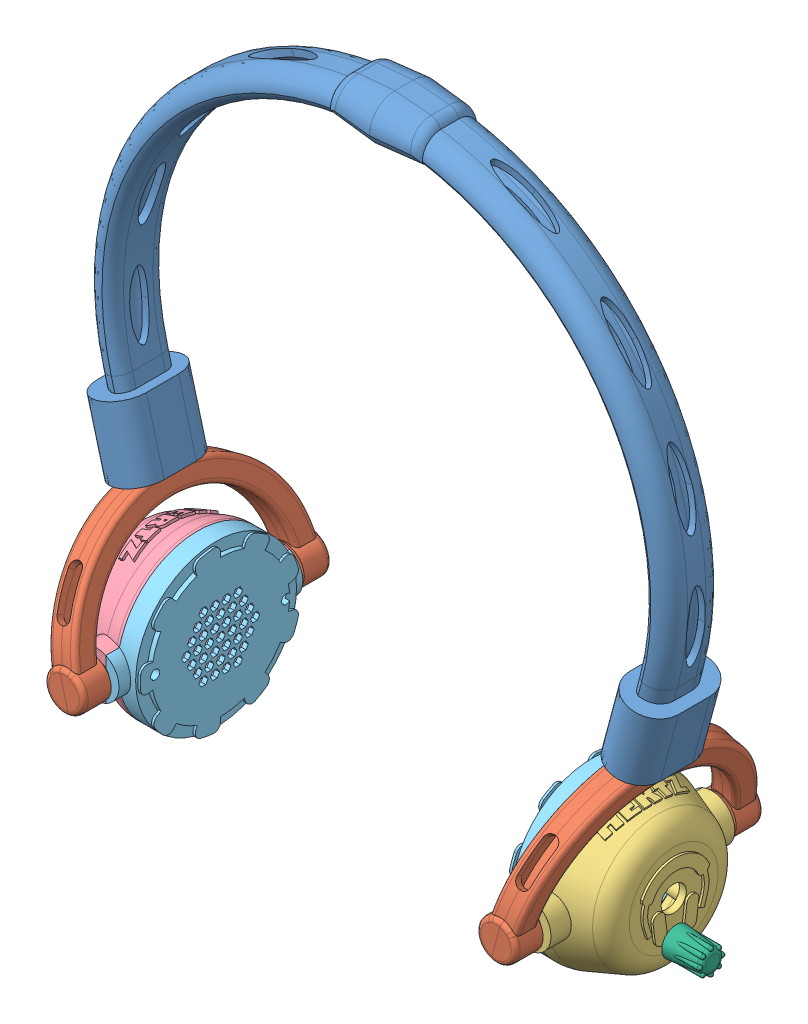
SolidWorks assembly Assem2, configuration Default. Lengths in mm.
Overall size (268.81 283.06 108).
11 component instances, 6 part files, 30 mates.
Components (placement in the parent):
- headband-1: headband [Default] at (155.2293 -27.012 122.3288) size (254.98 199.51 36)
- earcup_connector(sliced)-1: earcup_connector(sliced) [Default] at (142.6655 -16.2312 122.3288) x (0.965926 -0.258819 0) z (0 0 1) size (8.77 82.66 108)
- earcup_connector(sliced)-2: earcup_connector(sliced) [Default] at (-29.8486 -34.1436 122.3288) x (0.965926 0.258819 0) z (0 0 1) size (8.77 82.66 108)
- earcup_connector(sliced)-3: earcup_connector(sliced) [Default] at (37.0011 -16.2312 247.846) x (-0.965926 -0.258819 0) z (0 0 -1) size (8.77 82.66 108)
- earcup_connector(sliced)-4: earcup_connector(sliced) [Default] at (209.5153 -34.1436 247.846) x (-0.965926 0.258819 0) z (0 0 -1) size (8.77 82.66 108)
- earcup_r-1: earcup_r [Default] at (169.6258 4.7646 185.0874) x (0 0 -1) z (1 0 0) size (80 70.22 28.61)
- earcup_l-1: earcup_l [Default] at (10.0408 4.7646 185.0874) x (0 0 1) z (-1 0 0) size (80 70.22 28.61)
- earcup_lid-1: earcup_lid [Default] at (169.6258 4.8002 185.0874) x (0 -0.000416 -1) z (1 0 0) size (80 70 12)
- earcup_lid-2: earcup_lid [Default] at (10.0408 4.8002 185.0874) x (0 -0.000416 1) z (-1 0 0) size (80 70 12)
- pot_cap-1: pot_cap [Default] at (172.5866 -23.999 130.1325) x (1 0 0) z (0 0 1) size (16 12.45 12.45)
- pot_cap-2: pot_cap [Default] at (7.0801 2.3133 130.1455) x (-1 0 0) z (0 0 1) size (16 12.45 12.45)
Mates (geometry in assembly coordinates):
- Coincident1: coincident anti-aligned: plane of earcup_connector(sliced)-2 through (3.5762 -25.1874 122.3288) normal (-0.965926 -0.258819 0); plane of earcup_connector(sliced)-3 through (3.5762 -25.1874 247.846) normal (0.965926 0.258819 0)
- Coincident2: coincident anti-aligned: plane of earcup_connector(sliced)-1 through (176.0904 -25.1874 122.3288) normal (-0.965926 0.258819 0); plane of earcup_connector(sliced)-4 through (176.0904 -25.1874 247.846) normal (0.965926 -0.258819 0)
- Concentric1: concentric anti-aligned: circle of earcup_connector(sliced)-2; circle of earcup_connector(sliced)-3
- Concentric2: concentric anti-aligned: circle of earcup_connector(sliced)-1; circle of earcup_connector(sliced)-4
- Distance1: distance = 5 mm anti-aligned: plane of headband-1 through (-24.6339 80.0942 178.0874) normal (0.258819 -0.965926 0); plane of earcup_connector(sliced)-2 through (-23.3398 75.2646 179.0874) normal (-0.258819 0.965926 0)
- Distance2: distance = 5 mm anti-aligned: plane of earcup_connector(sliced)-1 through (203.0064 75.2646 179.0874) normal (0.258819 0.965926 0); plane of headband-1 through (204.3005 80.0942 178.0874) normal (-0.258819 -0.965926 0)
- Coincident8: coincident aligned: plane of earcup_connector(sliced)-1 through (203.0064 75.2646 179.0874) normal (0.258819 0.965926 0); plane of earcup_connector(sliced)-4 through (203.0064 75.2646 191.0874) normal (0.258819 0.965926 0)
- Coincident9: coincident aligned: plane of earcup_connector(sliced)-2 through (-23.3398 75.2646 179.0874) normal (-0.258819 0.965926 0); plane of earcup_connector(sliced)-3 through (-23.3398 75.2646 191.0874) normal (-0.258819 0.965926 0)
- Concentric9: concentric aligned: circle of earcup_l-1; circle of earcup_lid-2
- Concentric10: concentric aligned: circle of earcup_l-1; circle of earcup_lid-2
- Coincident11: coincident anti-aligned: plane of earcup_l-1; plane of earcup_lid-2
- Concentric11: concentric aligned: circle of earcup_r-1; circle of earcup_lid-1
- Concentric12: concentric aligned: circle of earcup_r-1; circle of earcup_lid-1
- Coincident12: coincident anti-aligned: plane of earcup_r-1; plane of earcup_lid-1
- Concentric13: concentric anti-aligned: circle of earcup_connector(sliced)-1; circle of earcup_r-1
- Concentric14: concentric aligned: circle of earcup_connector(sliced)-2; circle of earcup_l-1
- Width1: width anti-aligned: plane of earcup_connector(sliced)-4 through (183.8373 3.7244 143.0874) normal (0 0 1); plane of earcup_connector(sliced)-4 through (183.8373 3.7244 227.0874) normal (0 0 -1); plane of earcup_r-1 through (183.8373 3.7244 145.0874) normal (0 0 -1); plane of earcup_r-1 through (183.8373 3.7244 225.0874) normal (0 0 1)
- Width2: width anti-aligned: plane of earcup_connector(sliced)-3 through (-4.1706 3.7244 143.0874) normal (0 0 1); plane of earcup_connector(sliced)-3 through (-4.1706 3.7244 227.0874) normal (0 0 -1); plane of earcup_l-1 through (-4.1706 3.7244 145.0874) normal (0 0 -1); plane of earcup_l-1 through (-4.1706 3.7244 225.0874) normal (0 0 1)
- Width3: width anti-aligned: plane of headband-1 through (-17.8724 81.9059 178.0874) normal (-0.965926 -0.258819 0); plane of headband-1 through (-31.3954 78.2825 178.0874) normal (0.965926 0.258819 0); plane of earcup_connector(sliced)-2 through (1.6415 5.2153 134.0881) normal (0.965926 0.258819 0); plane of earcup_connector(sliced)-3 through (-9.9496 2.1095 236.0867) normal (-0.965926 -0.258819 0)
- Width4: width anti-aligned: plane of headband-1 through (197.539 81.9059 178.0874) normal (0.965926 -0.258819 0); plane of headband-1 through (211.062 78.2825 178.0874) normal (-0.965926 0.258819 0); plane of earcup_connector(sliced)-4 through (178.0251 5.2153 236.0867) normal (-0.965926 0.258819 0); plane of earcup_connector(sliced)-1 through (189.6162 2.1095 134.0881) normal (0.965926 -0.258819 0)
- Slot1: slot anti-aligned: plane of earcup_connector(sliced)-1 through (189.6162 2.1095 134.0881) normal (0.965926 -0.258819 0); plane of headband-1 through (211.062 78.2825 178.0874) normal (-0.965926 0.258819 0); cylinder of earcup_connector(sliced)-1 through (181.6112 -4.5835 191.0874) axis (0.258819 0.965926 0) radius 6; cylinder of headband-1 through (204.3005 80.0942 192.0874) axis (-0.258819 -0.965926 0) radius 7
- Slot2: slot anti-aligned: plane of earcup_connector(sliced)-3 through (-9.9496 2.1095 236.0867) normal (-0.965926 -0.258819 0); plane of headband-1 through (-31.3954 78.2825 178.0874) normal (0.965926 0.258819 0); cylinder of earcup_connector(sliced)-3 through (-1.9445 -4.5835 179.0874) axis (-0.258819 0.965926 0) radius 6; cylinder of headband-1 through (-24.6339 80.0942 178.0874) axis (0.258819 -0.965926 0) radius 7
- Concentric15: concentric aligned: circle of earcup_l-1; circle of pot_cap-2
- Concentric16: concentric aligned: circle of earcup_r-1; circle of pot_cap-1
- Parallel4: parallel anti-aligned: plane of earcup_r-1; plane of pot_cap-1
- Parallel5: parallel aligned: plane of earcup_l-1; plane of pot_cap-2
- Distance9: distance = 1 mm anti-aligned: plane of pot_cap-2; plane of earcup_l-1
- Distance10: distance = 1 mm anti-aligned: plane of pot_cap-1; plane of earcup_r-1
- LimitAngle1: limit planar angle = 3.403392 rad anti-aligned: plane of earcup_lid-1 through (169.6258 4.8002 185.0874) normal (-1 0 0); plane of headband-1 through (194.9694 87.7708 192.0874) normal (-0.965926 0.258819 0)
- LimitAngle2: limit planar angle = 3.403392 rad anti-aligned: plane of earcup_lid-2 through (10.0408 4.8002 185.0874) normal (1 0 0); plane of headband-1 through (-15.3028 87.7708 192.0874) normal (0.965926 0.258819 0)
